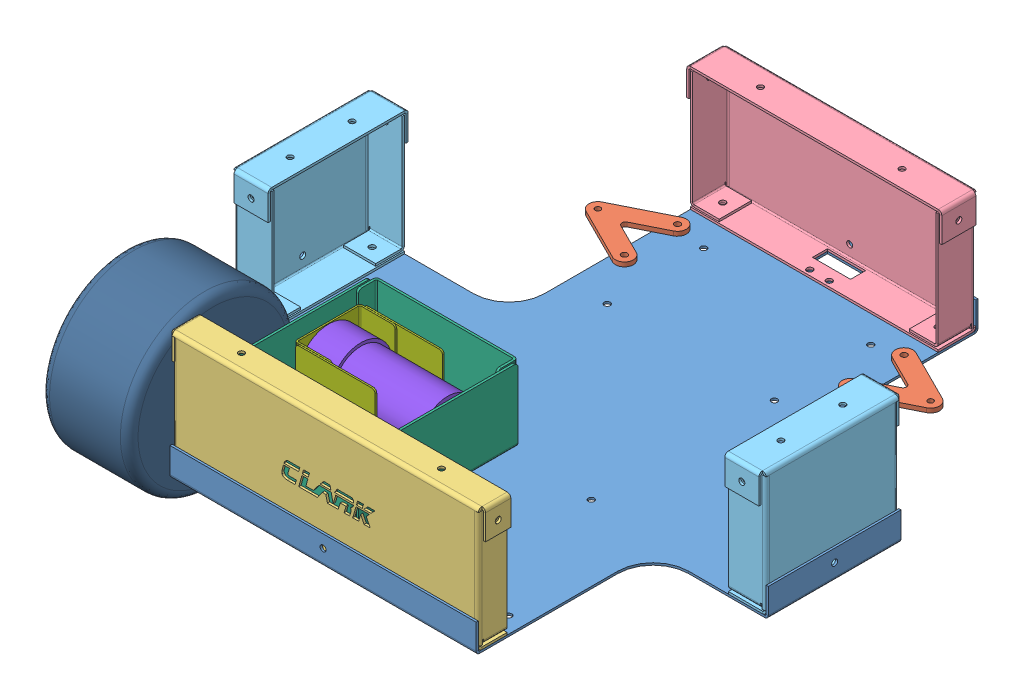
SolidWorks assembly ChassisLowerAssembly2, configuration Default. Lengths in mm.
Overall size (306 107.41 305.02).
16 component instances, 10 part files, 21 mates.
Components (placement in the parent):
- Chassis Base Level 0 (v3)-1: Chassis Base Level 0 (v3) [Default] at (-50.7661 -19.7833 139.8998) size (303 16.21 300)
- Front Wheel V-braket-1: Front Wheel V-braket [Default] at (129.7339 -19.7833 -109.3382) x (-1 0 0) z (0 0 1) size (40 2.42 40)
- Front Wheel V-braket-2: Front Wheel V-braket [Default] at (-58.2661 -17.3633 -109.3382) size (40 2.42 40)
- Chassis Wall South-1: Chassis Wall South [Default] at (122.2339 -19.7833 137.3998) x (-1 0 0) z (0 0 -1) size (177.1 70 16.29)
- Chassis Wall North-2: Chassis Wall North [Default] at (-34.2661 -19.7833 -157.6002) size (144.1 70 21.29)
- Chassis Wall East-1: Chassis Wall East [Default] at (-113.2661 -19.7833 39.8998) x (0 0 -1) z (1 0 0) size (79.1 70 21.29)
- Chassis Wall East-2: Chassis Wall East [Default] at (184.7339 -19.7833 -35.1002) x (0 0 1) z (-1 0 0) size (79.1 70 21.29)
- Gear Box Assembly-1: Gear Box Assembly [Default] at (-29.0739 24.9859 65.1587) x (0 0 -1) z (1 0 0) size (119.55 95 152.1)
  - Drive Gear Box-1: Drive Gear Box [Default] at (-52.2615 -43.4792 60.3599) size (94.1 41.29 84.1)
  - BarbCole Motor with Fixture-1: BarbCole Motor with Fixture [Default] at (16.6255 -14.6511 26.761) x (0 0 1) z (-1 0 0) size (89.87 36.41 55.14)
    - BarbCole Geared Fixture-1: BarbCole Geared Fixture [Default] at (-41.6291 -27.9181 27.027) size (67.26 36.41 55.14)
    - Motor BarbCole Geared-1: Motor BarbCole Geared [Default] at (-22.4819 -10.3495 9.4562) size (89.87 35.14 35.14)
  - socket head cap screw_am-1: socket head cap screw_am [B18.3.1M - 3 x 0.5 x 5 Hex SHCS -- 5NHX] at (-47.2615 -40.4792 53.3599) x (0 -1 0) z (0 0 1) size (8 5.5 5.5)
  - socket head cap screw_am-2: socket head cap screw_am [B18.3.1M - 3 x 0.5 x 5 Hex SHCS -- 5NHX] at (-47.2615 -40.4792 -12.6401) x (0 -1 0) z (0 0 1) size (8 5.5 5.5)
  - socket head cap screw_am-3: socket head cap screw_am [B18.3.1M - 3 x 0.5 x 5 Hex SHCS -- 5NHX] at (32.7385 -40.4792 20.725) x (0 -1 0) z (0 0 1) size (8 5.5 5.5)
  - Tire-1: Tire [Default] at (-32.2615 -34.6792 -89.6921) size (95 95 50)
Mates (geometry in assembly coordinates):
- Coincident4: coincident anti-aligned: plane of Chassis Base Level 0 (v3)-1 through (-50.7661 -19.7833 139.8998) normal (0 1 0); plane of Front Wheel V-braket-1 through (99.7339 -19.7833 -124.3382) normal (0 -1 0)
- Coincident5: coincident: line of Chassis Base Level 0 (v3)-1 through (-34.2661 -19.7833 -109.3382) axis (1 0 0); plane of Front Wheel V-braket-1 through (129.7339 -19.7833 -109.3382) normal (0 0 1)
- Distance1: distance = 6 mm aligned: plane of Front Wheel V-braket-1; plane of Chassis Base Level 0 (v3)-1 through (105.7339 -20.9933 -35.1002) normal (1 0 0)
- Coincident7: coincident anti-aligned: plane of Chassis Base Level 0 (v3)-1 through (-50.7661 -19.7833 139.8998) normal (0 1 0); plane of Front Wheel V-braket-2 through (-28.2661 -19.7833 -124.3382) normal (0 -1 0)
- Coincident8: coincident: line of Chassis Base Level 0 (v3)-1 through (-34.2661 -19.7833 -109.3382) axis (1 0 0); plane of Front Wheel V-braket-2 through (-58.2661 -17.3633 -109.3382) normal (0 0 1)
- Distance2: distance = 6 mm aligned: plane of Front Wheel V-braket-2 through (-28.2661 -17.3633 -109.3382) normal (-1 0 0); plane of Chassis Base Level 0 (v3)-1 through (-34.2661 -20.9933 -35.1002) normal (-1 0 0)
- Coincident10: coincident anti-aligned: plane of Chassis Base Level 0 (v3)-1 through (-50.7661 -19.7833 138.6898) normal (0 0 -1); plane of Chassis Wall South-1 through (122.2339 -19.7833 138.6898) normal (0 0 1)
- Coincident11: coincident anti-aligned: plane of Chassis Base Level 0 (v3)-1 through (-50.7661 -19.7833 139.8998) normal (0 1 0); plane of Chassis Wall South-1 through (122.2339 -19.7833 137.3998) normal (0 -1 0)
- Width1: width anti-aligned: plane of Chassis Wall South-1 through (122.2339 -19.7833 137.3998) normal (1 0 0); plane of Chassis Wall South-1 through (-50.7661 -19.7833 137.3998) normal (-1 0 0); plane of Chassis Base Level 0 (v3)-1 through (-50.7661 -20.9933 139.8998) normal (-1 0 0); plane of Chassis Base Level 0 (v3)-1 through (122.2339 -20.9933 139.8998) normal (1 0 0)
- Coincident12: coincident anti-aligned: plane of Chassis Base Level 0 (v3)-1 through (-50.7661 -19.7833 139.8998) normal (0 1 0); plane of Chassis Wall North-2 through (-34.2661 -19.7833 -157.6002) normal (0 -1 0)
- Coincident13: coincident anti-aligned: plane of Chassis Base Level 0 (v3)-1 through (-50.7661 -19.7833 -158.8902) normal (0 0 1); plane of Chassis Wall North-2 through (-34.2661 -19.7833 -158.8902) normal (0 0 -1)
- Width2: width aligned: plane of Chassis Wall North-2 through (-34.2661 -19.7833 -157.6002) normal (-1 0 0); plane of Chassis Wall North-2 through (105.7339 -19.7833 -157.6002) normal (1 0 0); plane of Chassis Base Level 0 (v3)-1 through (-34.2661 -20.9933 -35.1002) normal (-1 0 0); plane of Chassis Base Level 0 (v3)-1 through (105.7339 -20.9933 -35.1002) normal (1 0 0)
- Coincident14: coincident anti-aligned: plane of Chassis Base Level 0 (v3)-1 through (-50.7661 -19.7833 139.8998) normal (0 1 0); plane of Chassis Wall East-1 through (-113.2661 -19.7833 39.8998) normal (0 -1 0)
- Coincident15: coincident anti-aligned: plane of Chassis Base Level 0 (v3)-1 through (-114.5561 -19.7833 139.8998) normal (1 0 0); plane of Chassis Wall East-1 through (-114.5561 -19.7833 39.8998) normal (-1 0 0)
- Width3: width anti-aligned: plane of Chassis Wall East-1 through (-113.2661 -19.7833 -35.1002) normal (0 0 -1); plane of Chassis Wall East-1 through (-113.2661 -19.7833 39.8998) normal (0 0 1); plane of Chassis Base Level 0 (v3)-1 through (-50.7661 -20.9933 39.8998) normal (0 0 1); plane of Chassis Base Level 0 (v3)-1 through (-34.2661 -20.9933 -35.1002) normal (0 0 -1)
- Coincident16: coincident anti-aligned: plane of Chassis Base Level 0 (v3)-1 through (-50.7661 -19.7833 139.8998) normal (0 1 0); plane of Chassis Wall East-2 through (184.7339 -19.7833 -35.1002) normal (0 -1 0)
- Coincident17: coincident anti-aligned: plane of Chassis Base Level 0 (v3)-1 through (186.0239 -19.7833 139.8998) normal (-1 0 0); plane of Chassis Wall East-2 through (186.0239 -19.7833 -35.1002) normal (1 0 0)
- Width4: width anti-aligned: plane of Chassis Wall East-2 through (184.7339 -19.7833 39.8998) normal (0 0 1); plane of Chassis Wall East-2 through (184.7339 -19.7833 -35.1002) normal (0 0 -1); plane of Chassis Base Level 0 (v3)-1 through (105.7339 -20.9933 -35.1002) normal (0 0 -1); plane of Chassis Base Level 0 (v3)-1 through (122.2339 -20.9933 39.8998) normal (0 0 1)
- Coincident18: coincident anti-aligned: plane of Chassis Base Level 0 (v3)-1 through (-50.7661 -19.7833 139.8998) normal (0 1 0); plane of Gear Box Assembly-1/Drive Gear Box-1 through (31.2859 -19.7833 117.4202) normal (0 -1 0)
- Concentric1: concentric anti-aligned: cylinder of Chassis Base Level 0 (v3)-1 through (-8.3489 -20.9933 32.4202) axis (0 -1 0) radius 1.7; cylinder of Gear Box Assembly-1/Drive Gear Box-1 through (-8.3489 -18.4933 32.4202) axis (0 1 0) radius 1.7
- Concentric2: concentric anti-aligned: cylinder of Chassis Base Level 0 (v3)-1 through (24.2859 -20.9933 112.4202) axis (0 -1 0) radius 1.7; cylinder of Gear Box Assembly-1/Drive Gear Box-1 through (24.2859 -18.4933 112.4202) axis (0 1 0) radius 1.7
